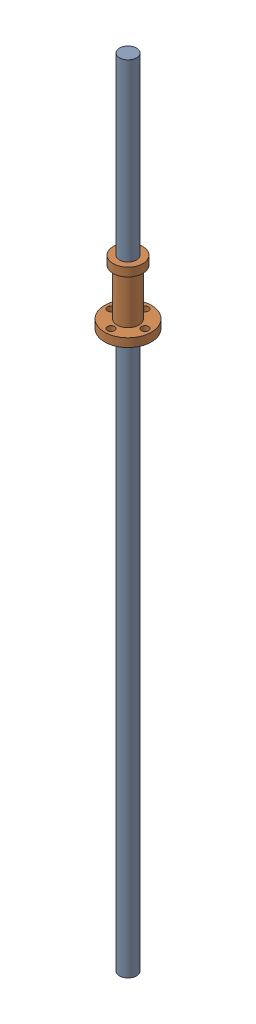
SolidWorks assembly z_leadscrew_with_nut_installed, configuration Default. Lengths in mm.
Overall size (22 375 22).
2 component instances, 2 part files, 0 mates.
Components (placement in the parent):
- acme_threaded_rod_mockup_375m-1: acme_threaded_rod_mockup_375m [Default] at (97.7051 62.1679 82.6328) x (-0.897579 0 0.440853) z (-0.440853 0 -0.897579) size (8 375 8)
- T8x2_lead_screw_antibacklash_delrin_nut-1: T8x2_lead_screw_antibacklash_delrin_nut [Default] at (97.7051 324.5953 82.6328) size (22 30 22)
